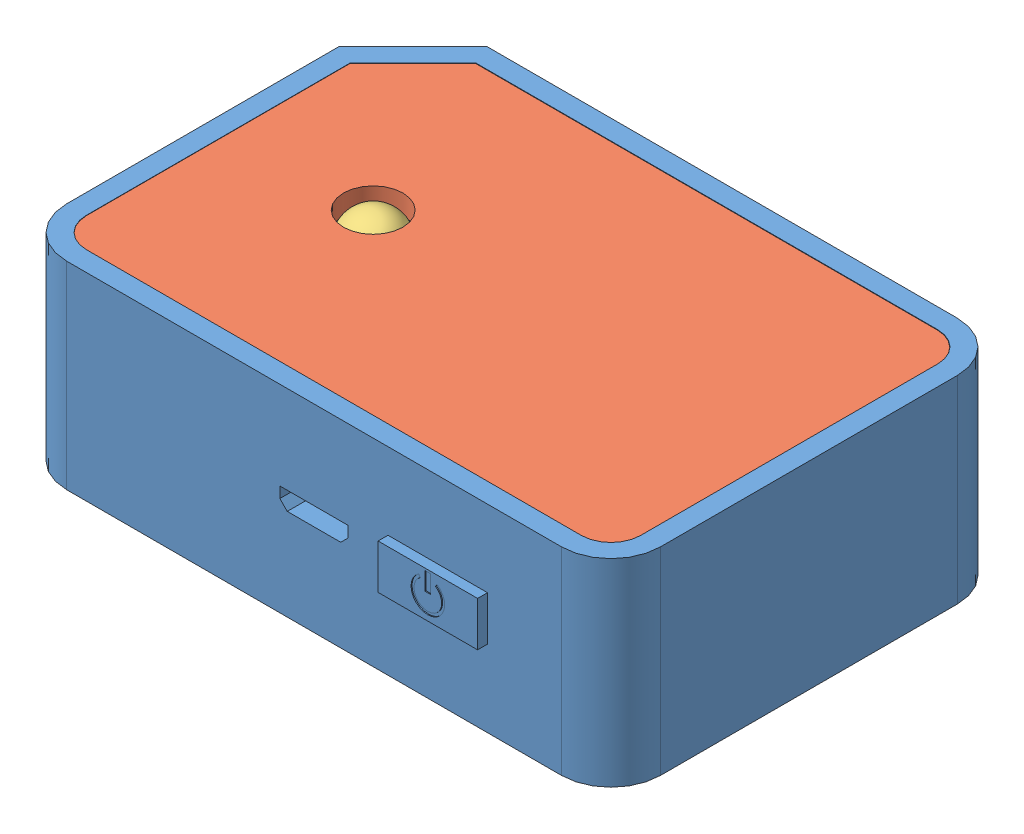
SolidWorks assembly wearable tracker, configuration Default. Lengths in mm.
Overall size (60 20.11 41).
3 component instances, 3 part files, 0 mates.
Components (placement in the parent):
- basenew-1: basenew [Default] at (27.448 18.8337 37.3875) size (60 20 41)
- topnew-1: topnew [Default] at (46.2829 36.7995 67.6639) size (56 2 36)
- Lednew-1: Lednew [Default] at (40.831 32.9418 57.477) size (6 6 6)
